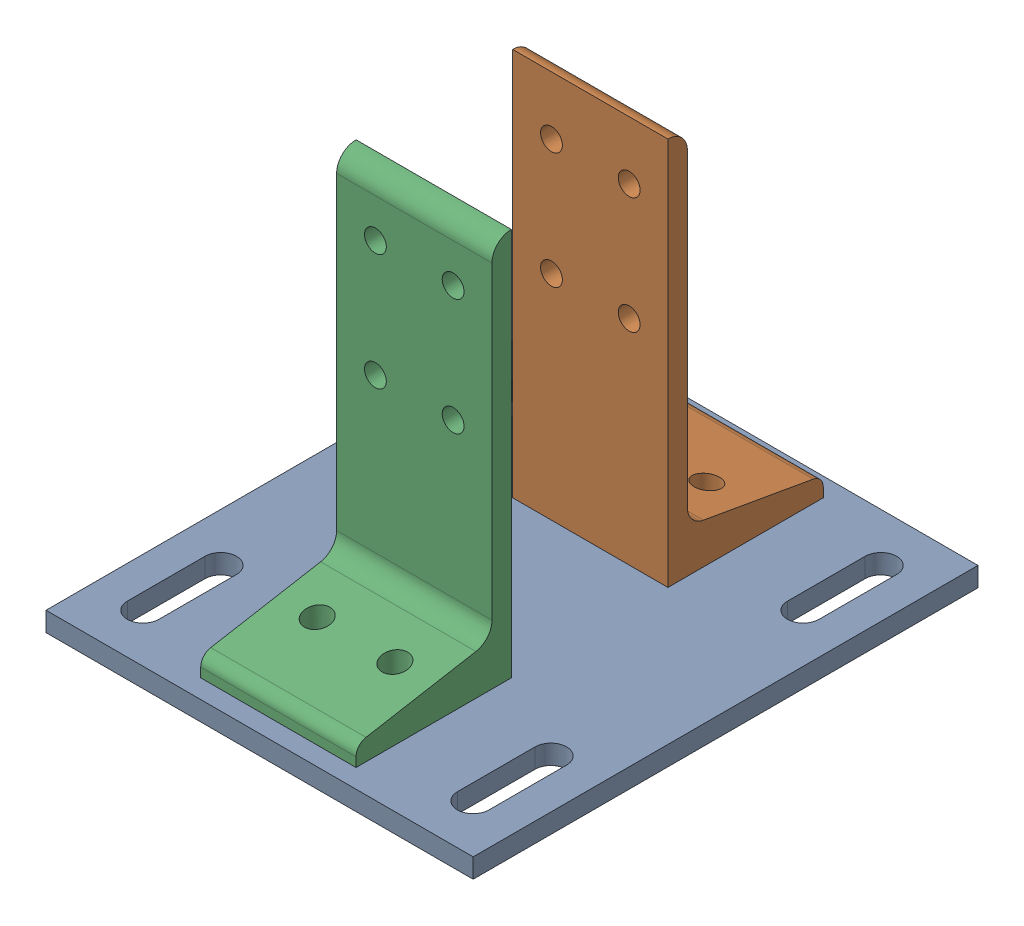
SolidWorks assembly Mirror8020-2387-DEFAULT, configuration Default. Lengths in mm.
Overall size (139.7 133.35 165.1).
3 component instances, 2 part files, 0 mates.
Components (placement in the parent):
- Mirror8020-2387-DEFAULT_238708-1: Mirror8020-2387-DEFAULT_238708 [Default] at (-67.1549 7.3704 -27.8119) size (139.7 6.35 165.1)
- Mirror8020-2387-DEFAULT_238509-1: Mirror8020-2387-DEFAULT_238509 [Default] at (9.1264 0.0214 -49.7635) x (0 0 -1) z (1 0 0) size (50.8 127 50.8)
- Mirror8020-2387-DEFAULT_238509-2: Mirror8020-2387-DEFAULT_238509 [Default] at (-41.6736 0.0214 46.9187) x (0 0 1) z (-1 0 0) size (50.8 127 50.8)
